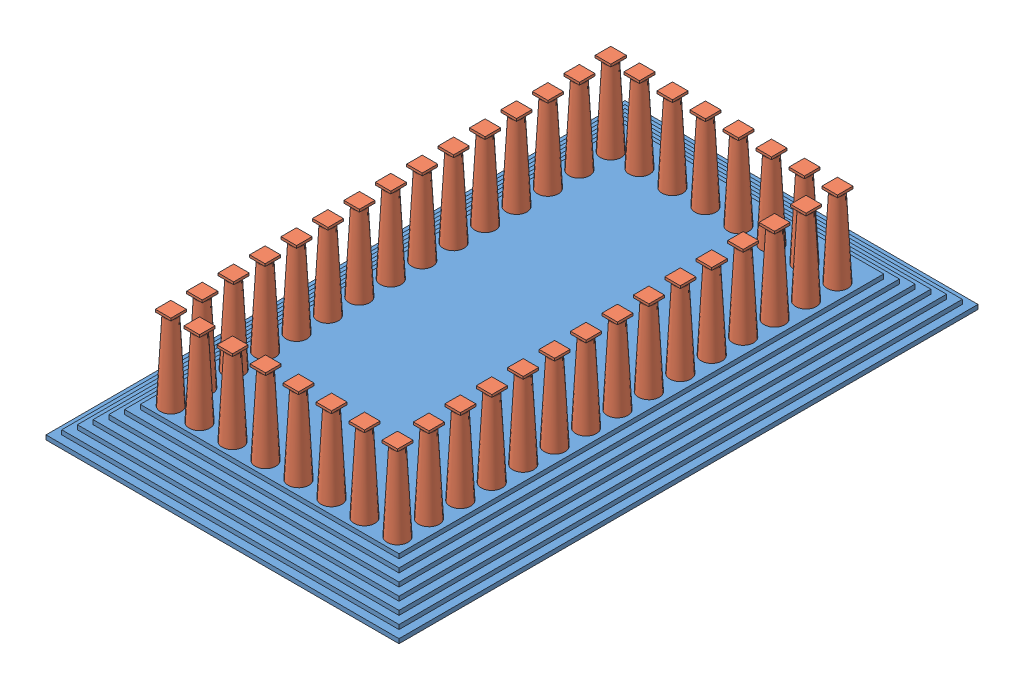
SolidWorks assembly assem_final2base, configuration Default. Lengths in mm.
Overall size (44.94 14.64 73.7).
44 component instances, 2 part files, 1 mates.
Components (placement in the parent):
- parthenon_base-1: parthenon_base [Default] at (-11.0896 3.1982 28.3251) size (44.94 3.92 73.7)
- parthenon_pillar-2: parthenon_pillar [Default] at (9.9021 3.2982 -4.2756) x (1 0 0) z (0 1 0) size (2.64 2.64 10.63)
- parthenon_pillar-3: parthenon_pillar [Default] at (9.9021 3.2982 -8.2756) x (1 0 0) z (0 1 0) size (2.64 2.64 10.63)
- parthenon_pillar-4: parthenon_pillar [Default] at (9.9021 3.2982 -12.2756) x (1 0 0) z (0 1 0) size (2.64 2.64 10.63)
- parthenon_pillar-5: parthenon_pillar [Default] at (9.9021 3.2982 -16.2756) x (1 0 0) z (0 1 0) size (2.64 2.64 10.63)
- parthenon_pillar-6: parthenon_pillar [Default] at (9.9021 3.2982 -20.2756) x (1 0 0) z (0 1 0) size (2.64 2.64 10.63)
- parthenon_pillar-7: parthenon_pillar [Default] at (9.9021 3.2982 -24.2756) x (1 0 0) z (0 1 0) size (2.64 2.64 10.63)
- parthenon_pillar-8: parthenon_pillar [Default] at (9.9021 3.2982 -28.2756) x (1 0 0) z (0 1 0) size (2.64 2.64 10.63)
- parthenon_pillar-9: parthenon_pillar [Default] at (9.9021 3.2982 -32.2756) x (1 0 0) z (0 1 0) size (2.64 2.64 10.63)
- parthenon_pillar-10: parthenon_pillar [Default] at (9.9021 3.2982 -36.2756) x (1 0 0) z (0 1 0) size (2.64 2.64 10.63)
- parthenon_pillar-11: parthenon_pillar [Default] at (9.9021 3.2982 -40.2756) x (1 0 0) z (0 1 0) size (2.64 2.64 10.63)
- parthenon_pillar-12: parthenon_pillar [Default] at (9.9021 3.2982 -44.2756) x (1 0 0) z (0 1 0) size (2.64 2.64 10.63)
- parthenon_pillar-13: parthenon_pillar [Default] at (9.9021 3.2982 -48.2756) x (1 0 0) z (0 1 0) size (2.64 2.64 10.63)
- parthenon_pillar-14: parthenon_pillar [Default] at (9.9021 3.2982 -52.2756) x (1 0 0) z (0 1 0) size (2.64 2.64 10.63)
- parthenon_pillar-15: parthenon_pillar [Default] at (9.9021 3.2982 -56.2756) x (1 0 0) z (0 1 0) size (2.64 2.64 10.63)
- parthenon_pillar-16: parthenon_pillar [Default] at (9.9021 3.2982 -60.2756) x (1 0 0) z (0 1 0) size (2.64 2.64 10.63)
- parthenon_pillar-17: parthenon_pillar [Default] at (-18.9519 3.2982 -4.2756) x (1 0 0) z (0 1 0) size (2.64 2.64 10.63)
- parthenon_pillar-18: parthenon_pillar [Default] at (-18.9519 3.2982 -8.2756) x (1 0 0) z (0 1 0) size (2.64 2.64 10.63)
- parthenon_pillar-19: parthenon_pillar [Default] at (-18.9519 3.2982 -12.2756) x (1 0 0) z (0 1 0) size (2.64 2.64 10.63)
- parthenon_pillar-20: parthenon_pillar [Default] at (-18.9519 3.2982 -16.2756) x (1 0 0) z (0 1 0) size (2.64 2.64 10.63)
- parthenon_pillar-21: parthenon_pillar [Default] at (-18.9519 3.2982 -20.2756) x (1 0 0) z (0 1 0) size (2.64 2.64 10.63)
- parthenon_pillar-22: parthenon_pillar [Default] at (-18.9519 3.2982 -24.2756) x (1 0 0) z (0 1 0) size (2.64 2.64 10.63)
- parthenon_pillar-23: parthenon_pillar [Default] at (-18.9519 3.2982 -28.2756) x (1 0 0) z (0 1 0) size (2.64 2.64 10.63)
- parthenon_pillar-24: parthenon_pillar [Default] at (-18.9519 3.2982 -32.2756) x (1 0 0) z (0 1 0) size (2.64 2.64 10.63)
- parthenon_pillar-25: parthenon_pillar [Default] at (-18.9519 3.2982 -36.2756) x (1 0 0) z (0 1 0) size (2.64 2.64 10.63)
- parthenon_pillar-26: parthenon_pillar [Default] at (-18.9519 3.2982 -40.2756) x (1 0 0) z (0 1 0) size (2.64 2.64 10.63)
- parthenon_pillar-27: parthenon_pillar [Default] at (-18.9519 3.2982 -44.2756) x (1 0 0) z (0 1 0) size (2.64 2.64 10.63)
- parthenon_pillar-28: parthenon_pillar [Default] at (-18.9519 3.2982 -48.2756) x (1 0 0) z (0 1 0) size (2.64 2.64 10.63)
- parthenon_pillar-29: parthenon_pillar [Default] at (-18.9519 3.2982 -52.2756) x (1 0 0) z (0 1 0) size (2.64 2.64 10.63)
- parthenon_pillar-30: parthenon_pillar [Default] at (-18.9519 3.2982 -56.2756) x (1 0 0) z (0 1 0) size (2.64 2.64 10.63)
- parthenon_pillar-31: parthenon_pillar [Default] at (-18.9519 3.2982 -60.2756) x (1 0 0) z (0 1 0) size (2.64 2.64 10.63)
- parthenon_pillar-32: parthenon_pillar [Default] at (5.7021 3.2982 -4.2756) x (1 0 0) z (0 1 0) size (2.64 2.64 10.63)
- parthenon_pillar-33: parthenon_pillar [Default] at (1.5021 3.2982 -4.2756) x (1 0 0) z (0 1 0) size (2.64 2.64 10.63)
- parthenon_pillar-34: parthenon_pillar [Default] at (-2.6979 3.2982 -4.2756) x (1 0 0) z (0 1 0) size (2.64 2.64 10.63)
- parthenon_pillar-35: parthenon_pillar [Default] at (-6.8979 3.2982 -4.2756) x (1 0 0) z (0 1 0) size (2.64 2.64 10.63)
- parthenon_pillar-36: parthenon_pillar [Default] at (-11.0979 3.2982 -4.2756) x (1 0 0) z (0 1 0) size (2.64 2.64 10.63)
- parthenon_pillar-37: parthenon_pillar [Default] at (-15.2979 3.2982 -4.2756) x (1 0 0) z (0 1 0) size (2.64 2.64 10.63)
- parthenon_pillar-38: parthenon_pillar [Default] at (9.9021 3.2982 -60.2756) x (1 0 0) z (0 1 0) size (2.64 2.64 10.63)
- parthenon_pillar-39: parthenon_pillar [Default] at (5.7021 3.2982 -60.2756) x (1 0 0) z (0 1 0) size (2.64 2.64 10.63)
- parthenon_pillar-40: parthenon_pillar [Default] at (1.5021 3.2982 -60.2756) x (1 0 0) z (0 1 0) size (2.64 2.64 10.63)
- parthenon_pillar-41: parthenon_pillar [Default] at (-2.6979 3.2982 -60.2756) x (1 0 0) z (0 1 0) size (2.64 2.64 10.63)
- parthenon_pillar-42: parthenon_pillar [Default] at (-6.8979 3.2982 -60.2756) x (1 0 0) z (0 1 0) size (2.64 2.64 10.63)
- parthenon_pillar-43: parthenon_pillar [Default] at (-11.0979 3.2982 -60.2756) x (1 0 0) z (0 1 0) size (2.64 2.64 10.63)
- parthenon_pillar-44: parthenon_pillar [Default] at (-15.2979 3.2982 -60.2756) x (1 0 0) z (0 1 0) size (2.64 2.64 10.63)
Mates (geometry in assembly coordinates):
- Coincident2: coincident: plane of parthenon_base-1 through (-11.0896 3.1982 28.3251) normal (0 1 0); plane of parthenon_pillar-2 through (17.7554 3.1982 26.6148) normal (0 -1 0)
